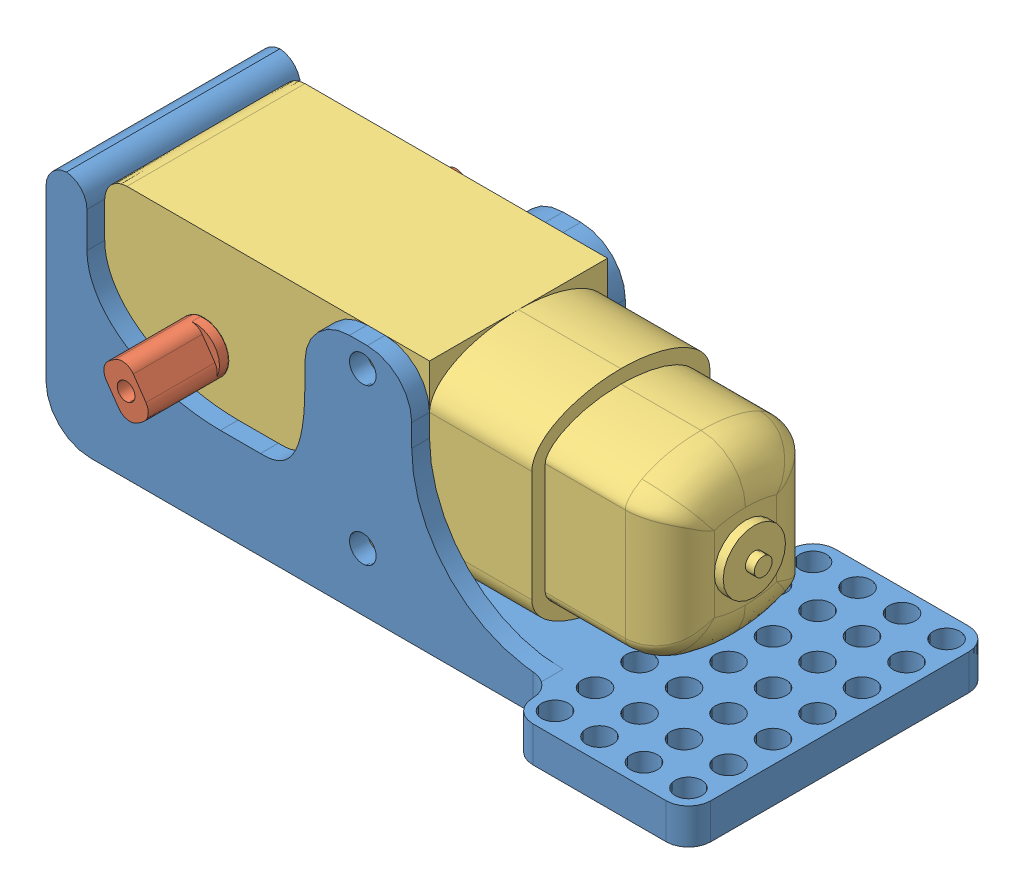
SolidWorks assembly dc_motor_2, configuration Défaut. Lengths in mm.
Overall size (77.2 26.55 37.5).
3 component instances, 3 part files, 4 mates.
Components (placement in the parent):
- DC_motor_adapter_2-1: DC_motor_adapter_2 [Défaut] at (-41.277 -6.8261 92.2) size (77.2 26.55 35)
- axis_gear_motor-1: axis_gear_motor [Default] at (-31.3629 2.3802 82.2) x (0.569545 -0.82196 0) z (0 0 1) size (5.6 5.6 37.5)
- body_gear_motor-1: body_gear_motor [Default] at (-18.427 6.4239 82.2) x (0 1 0) z (0 0 1) size (22.6 68.6 21.65)
Mates (geometry in assembly coordinates):
- Coaxiale1: concentric: cylinder of axis_gear_motor-1 through (-25.527 6.4239 41.95) axis (0 0 1) radius 2.7981; cylinder of body_gear_motor-1 through (-25.527 6.4239 41.95) axis (0 0 1) radius 2.7981
- Distance1: distance = 0 mm: plane of axis_gear_motor-1 through (-49.4088 -23.8108 92.2) normal (0 0 1); plane of body_gear_motor-1 through (11.323 17.6739 92.2) normal (0 0 1)
- Coïncidente2: coincident: plane of DC_motor_adapter_2-1 through (-41.277 -6.8261 92.2) normal (0 0 -1); plane of body_gear_motor-1 through (11.323 17.6739 92.2) normal (0 0 1)
- Coïncidente4: coincident: plane of DC_motor_adapter_2-1 through (-36.677 17.6739 94.2) normal (1 0 0); plane of body_gear_motor-1 through (-36.677 17.6739 92.2) normal (-1 0 0)
